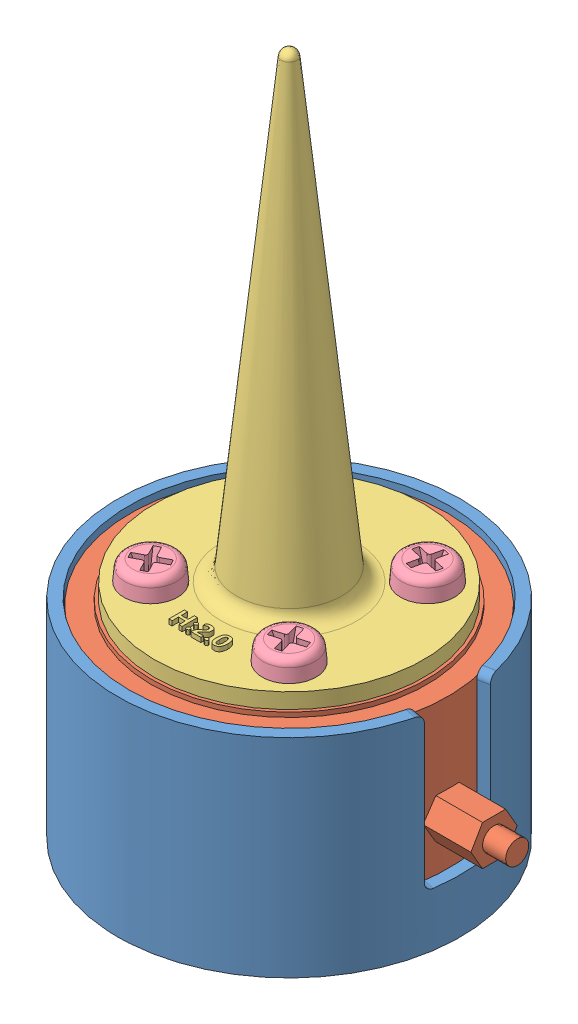
SolidWorks assembly press_v2, configuration 默认. Lengths in mm.
Overall size (51.85 91.4 44.5).
12 component instances, 4 part files, 23 mates.
Components (placement in the parent):
- press_outer_v2-1: press_outer_v2 [默认] at (1.882 -6.7987 44.5) size (44.5 27.66 44.5)
- press_sensor_v2-1: press_sensor_v2 [默认] at (1.882 -3.5987 44.5) size (50.2 23.6 41.2)
- press_ indenter_v2-1: press_ indenter_v2 [默认] at (1.882 20.0013 44.5) size (35 64 35)
- cross recessed cheese head screws gb-1: cross recessed cheese head screws gb [GB_CROSS_SCREWS_TYPE2 M4X8-8  H type-N] at (10.8622 -9.3987 53.4803) x (0 1 0) z (0.946599 0 0.322412) size (10.6 7 7)
- cross recessed cheese head screws gb-3: cross recessed cheese head screws gb [GB_CROSS_SCREWS_TYPE2 M4X8-8  H type-N] at (-7.0983 -9.3987 35.5197) x (0 1 0) z (0 0 1) size (10.6 7 7)
- cross recessed cheese head screws gb-4: cross recessed cheese head screws gb [GB_CROSS_SCREWS_TYPE2 M4X8-8  H type-N] at (-7.0983 -9.3987 53.4803) x (0 1 0) z (0.063608 0 0.997975) size (10.6 7 7)
- cross recessed cheese head screws gb-5: cross recessed cheese head screws gb [GB_CROSS_SCREWS_TYPE2 M4X8-8  H type-N] at (10.8622 -9.3987 35.5197) x (0 1 0) z (0.986903 0 0.161314) size (10.6 7 7)
- cross recessed cheese head screws gb-7: cross recessed cheese head screws gb [GB_CROSS_SCREWS_TYPE2 M4X8-8  H type-N] at (1.882 11.1905 44.5) x (0 -1 0) z (0 0 1) size (10.6 7 7)
- cross recessed cheese head screws gb-8: cross recessed cheese head screws gb [GB_CROSS_SCREWS_TYPE2 M4X6-6  H type-N] at (10.8622 24.6013 53.4803) x (0 -1 0) z (0.962054 0 -0.272861) size (8.6 7 7)
- cross recessed cheese head screws gb-9: cross recessed cheese head screws gb [GB_CROSS_SCREWS_TYPE2 M4X6-6  H type-N] at (10.8622 24.6013 35.5197) x (0 -1 0) z (0.216019 0 -0.976389) size (8.6 7 7)
- cross recessed cheese head screws gb-10: cross recessed cheese head screws gb [GB_CROSS_SCREWS_TYPE2 M4X6-6  H type-N] at (-7.0983 24.6013 35.5197) x (0 -1 0) z (-0.203283 0 -0.97912) size (8.6 7 7)
- cross recessed cheese head screws gb-11: cross recessed cheese head screws gb [GB_CROSS_SCREWS_TYPE2 M4X6-6  H type-N] at (-7.0983 24.6013 53.4803) x (0 -1 0) z (0.883633 0 -0.468181) size (8.6 7 7)
Mates (geometry in assembly coordinates):
- 重合1: coincident anti-aligned: plane of press_outer_v2-1 through (1.882 -3.5987 44.5) normal (0 1 0); plane of press_sensor_v2-1 through (1.882 -3.5987 44.5) normal (0 -1 0)
- 同心1: concentric anti-aligned: circle of press_outer_v2-1; circle of press_sensor_v2-1
- 同心2: concentric aligned: circle of press_outer_v2-1; circle of press_sensor_v2-1
- 同心3: concentric anti-aligned: circle of press_sensor_v2-1; circle of press_ indenter_v2-1
- 重合11: coincident anti-aligned: plane of press_sensor_v2-1 through (1.882 20.0013 44.5) normal (0 1 0); plane of press_ indenter_v2-1 through (1.882 20.0013 44.5) normal (0 -1 0)
- 同心4: concentric aligned: circle of press_outer_v2-1; circle of press_ indenter_v2-1
- 重合19: coincident anti-aligned: plane of press_outer_v2-1 through (1.882 -6.7987 44.5) normal (0 -1 0); plane of cross recessed cheese head screws gb-5 through (10.4912 -6.7987 37.7896) normal (0 1 0)
- 同心6: concentric aligned: circle of press_sensor_v2-1; circle of cross recessed cheese head screws gb-5
- 重合25: coincident anti-aligned: plane of press_outer_v2-1 through (1.882 -6.7987 44.5) normal (0 -1 0); plane of cross recessed cheese head screws gb-1 through (10.1207 -6.7987 55.6574) normal (0 1 0)
- 同心7: concentric aligned: circle of press_outer_v2-1; circle of cross recessed cheese head screws gb-1
- 重合26: coincident anti-aligned: plane of press_outer_v2-1 through (1.882 -6.7987 44.5) normal (0 -1 0); plane of cross recessed cheese head screws gb-3 through (-9.3983 -6.7987 35.5197) normal (0 1 0)
- 同心8: concentric aligned: circle of press_outer_v2-1; circle of cross recessed cheese head screws gb-3
- 同心9: concentric aligned: circle of press_outer_v2-1; circle of cross recessed cheese head screws gb-4
- 重合27: coincident anti-aligned: plane of press_outer_v2-1 through (1.882 -6.7987 44.5) normal (0 -1 0); plane of cross recessed cheese head screws gb-4 through (-9.3936 -6.7987 53.6266) normal (0 1 0)
- 同心10: concentric aligned: cylinder of press_outer_v2-1 through (1.882 20.2013 44.5) axis (0 -1 0) radius 22.25; cylinder of cross recessed cheese head screws gb-7 through (1.882 6.6747 44.5) axis (0 -1 0) radius 2
- 重合28: coincident anti-aligned: plane of press_ indenter_v2-1 through (1.882 22.0013 44.5) normal (0 1 0); plane of cross recessed cheese head screws gb-8 through (10.2347 22.0013 51.2675) normal (0 -1 0)
- 同心12: concentric aligned: circle of press_ indenter_v2-1; circle of cross recessed cheese head screws gb-8
- 同心13: concentric aligned: circle of press_sensor_v2-1; circle of cross recessed cheese head screws gb-9
- 同心14: concentric aligned: circle of press_sensor_v2-1; circle of cross recessed cheese head screws gb-10
- 同心15: concentric aligned: circle of press_ indenter_v2-1; circle of cross recessed cheese head screws gb-11
- 重合29: coincident anti-aligned: plane of press_ indenter_v2-1 through (1.882 22.0013 44.5) normal (0 1 0); circle of cross recessed cheese head screws gb-10
- 重合30: coincident anti-aligned: plane of press_ indenter_v2-1 through (1.882 22.0013 44.5) normal (0 1 0); circle of cross recessed cheese head screws gb-9
- 重合31: coincident anti-aligned: plane of press_ indenter_v2-1 through (1.882 22.0013 44.5) normal (0 1 0); plane of cross recessed cheese head screws gb-11 through (-8.1751 22.0013 51.4479) normal (0 -1 0)
